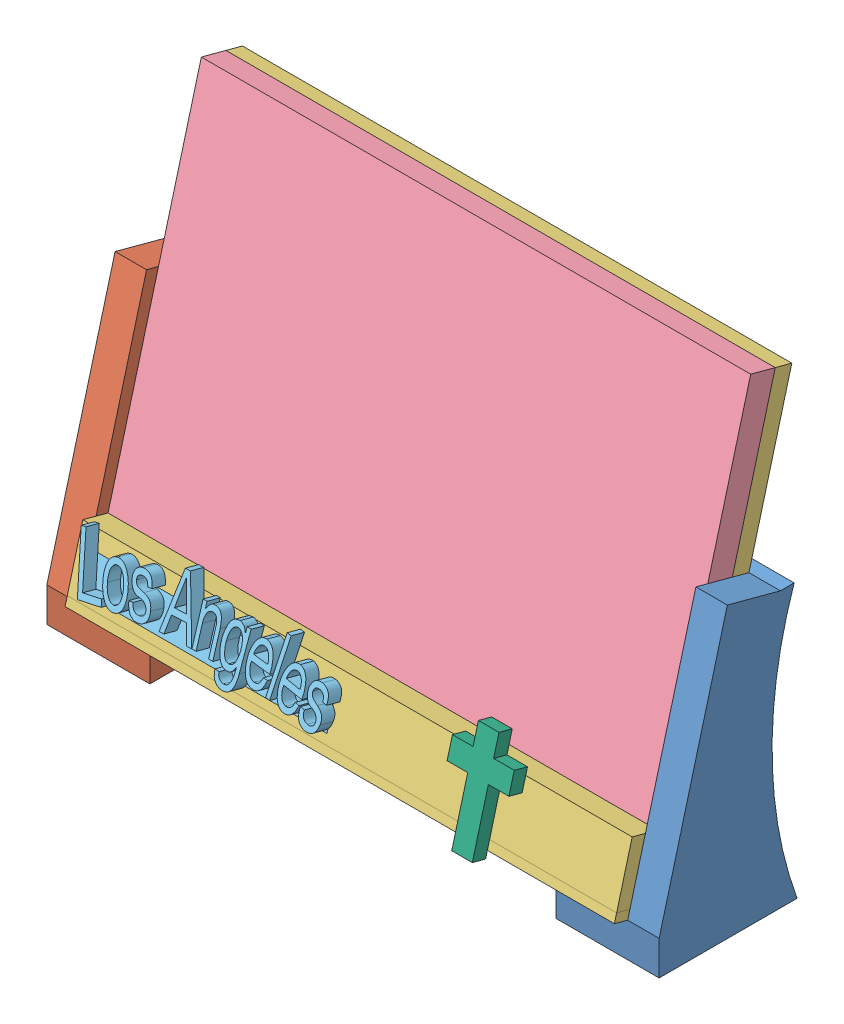
SolidWorks assembly Frame Assebly, configuration Default. Lengths in mm.
Overall size (226.48 167.36 71.19).
6 component instances, 6 part files, 19 mates.
Components (placement in the parent):
- 1-1: 1 [Default] at (-44.4789 0 30.627) size (38.1 106.86 51.04)
- 2-1: 2 [Default] at (-194.7599 0 30.627) size (38.1 106.86 51.04)
- 3-1: 3 [Default] at (-221.2194 7.4408 10.9994) x (1 0 0) z (0 0.258819 0.965926) size (203.2 158.75 25.4)
- 4-1: 4 [Default] at (-221.2194 15.2179 15.4895) x (1 0 0) z (0 0.258819 0.965926) size (203.2 152.4 9.4)
- 6-1: 6 [Default] at (-214.8694 18.5049 27.7568) x (1 0 0) z (0 -0.965926 0.258819) size (93.47 11.43 26.54)
- 7-1: 7 [Default] at (-72.6294 11.5613 36.1913) x (1 0 0) z (0 0.258819 0.965926) size (22.86 38.1 10.16)
Mates (geometry in assembly coordinates):
- Coincident1: coincident anti-aligned: plane of 2-1 through (-232.8599 0 30.627) normal (0 -1 0); plane of assembly through (0 0 0) normal (0 1 0)
- Coincident2: coincident anti-aligned: plane of 1-1 through (-6.3789 0 30.627) normal (0 -1 0); plane of assembly through (0 0 0) normal (0 1 0)
- Coincident3: coincident aligned: plane of 1-1 through (-6.3789 12.7 30.627) normal (0 0 1); plane of 2-1 through (-232.8599 12.7 30.627) normal (0 0 1)
- Coincident5: coincident anti-aligned: plane of 2-1 through (-232.8599 7.4408 10.9994) normal (0 0.258819 0.965926); plane of 3-1 through (-221.2194 7.4408 10.9994) normal (0 -0.258819 -0.965926)
- Coincident6: coincident anti-aligned: plane of 2-1 through (-221.2194 106.8592 5.3971) normal (1 0 0); plane of 3-1 through (-221.2194 162.425 -23.9545) normal (-1 0 0)
- Coincident7: coincident anti-aligned: plane of 1-1 through (-18.0194 106.8592 5.3971) normal (-1 0 0); plane of 3-1 through (-18.0194 162.425 -23.9545) normal (1 0 0)
- Coincident8: coincident anti-aligned: plane of 2-1 through (-232.8599 12.7 30.627) normal (0 0.965926 -0.258819); plane of 3-1 through (-221.2194 9.0843 17.133) normal (0 -0.965926 0.258819)
- Coincident9: coincident anti-aligned: plane of 3-1 through (-221.2194 9.0843 17.133) normal (0 0.258819 0.965926); plane of 4-1 through (-221.2194 15.2179 15.4895) normal (0 -0.258819 -0.965926)
- Coincident10: coincident anti-aligned: plane of 3-1 through (-221.2194 20.1484 33.8904) normal (0 0.965926 -0.258819); plane of 4-1 through (-221.2194 17.6503 24.5673) normal (0 -0.965926 0.258819)
- Coincident11: coincident anti-aligned: plane of 2-1 through (-221.2194 106.8592 5.3971) normal (1 0 0); plane of 4-1 through (-221.2194 17.6503 24.5673) normal (-1 0 0)
- Coincident13: coincident anti-aligned: plane of 3-1 through (-221.2194 14.0148 54.6969) normal (0 0.258819 0.965926); plane of ? through (-41.1887 39.8903 47.7636) normal (0 -0.258819 -0.965926)
- Concentric1: concentric aligned: cylinder of 3-1 through (-68.8194 24.6147 25.5596) axis (0 0.258819 0.965926) radius 1.905; cylinder of ? through (-68.8194 29.2168 42.7347) axis (0 0.258819 0.965926) radius 1.905
- Concentric2: concentric anti-aligned: circle of 3-1; circle of ?
- Coincident18: coincident aligned: plane of 3-1 through (-221.2194 14.0148 35.5339) normal (0 0.258819 0.965926); plane of 6-1 through (-214.8694 20.1484 33.8904) normal (0 0.258819 0.965926)
- Coincident19: coincident anti-aligned: plane of 3-1 through (-214.8694 30.4435 23.243) normal (1 0 0); plane of 6-1 through (-214.8694 20.1484 33.8904) normal (-1 0 0)
- Coincident20: coincident anti-aligned: plane of 3-1 through (-214.8694 18.1762 26.53) normal (0 0.965926 -0.258819); plane of 6-1 through (-214.8694 20.1484 33.8904) normal (0 -0.965926 0.258819)
- Concentric3: concentric: cylinder of 3-1 through (-68.8194 17.2543 8.3688) axis (0 0.258819 0.965926) radius 1.905; cylinder of 7-1 through (-68.8194 22.5138 27.9974) axis (0 0.258819 0.965926) radius 1.27
- Concentric4: concentric: cylinder of 3-1 through (-68.8194 24.6147 6.3966) axis (0 0.258819 0.965926) radius 1.905; cylinder of 7-1 through (-68.8194 29.8742 26.0252) axis (0 0.258819 0.965926) radius 1.27
- Coincident21: coincident anti-aligned: plane of 3-1 through (-221.2194 14.0148 35.5339) normal (0 0.258819 0.965926); plane of 7-1 through (-72.6294 11.5613 36.1913) normal (0 -0.258819 -0.965926)
